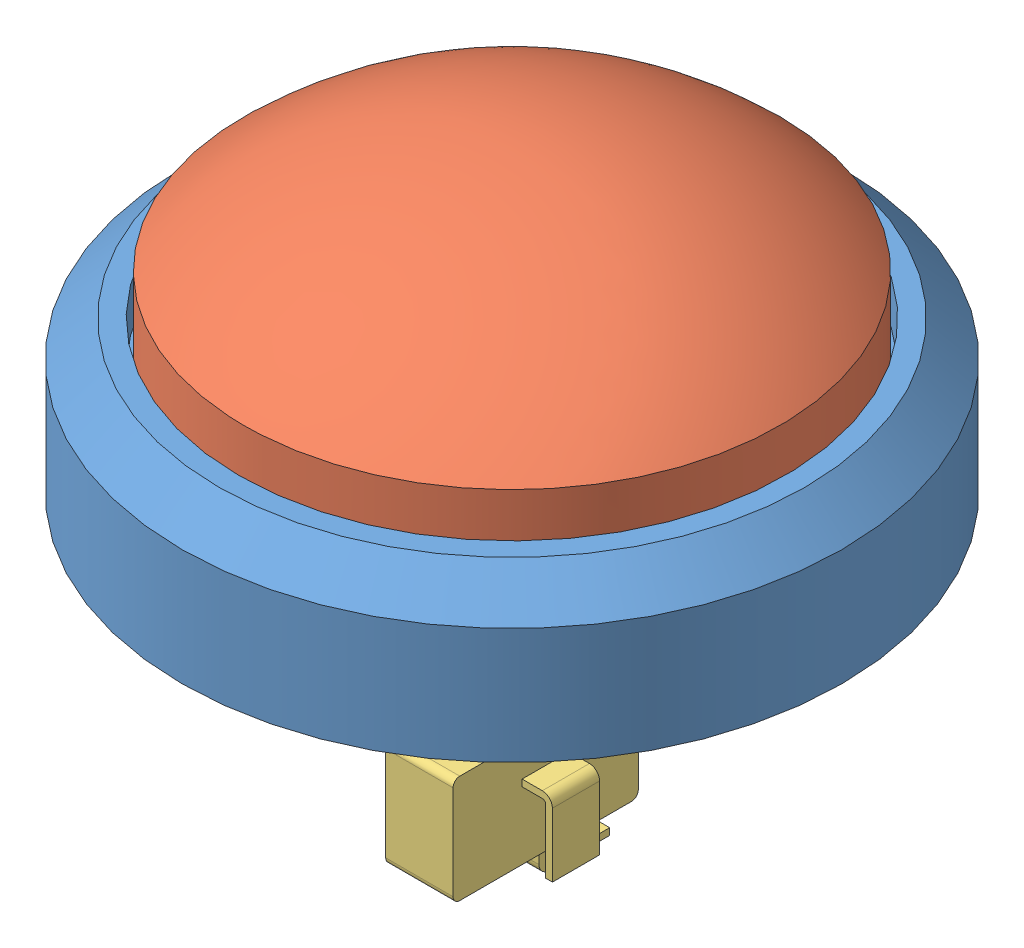
SolidWorks assembly Button Assembly, configuration Default. Lengths in mm.
Overall size (98 92.55 98).
3 component instances, 3 part files, 5 mates.
Components (placement in the parent):
- Button Shield-2: Button Shield [Default] at (4.0062 3.8785 -7.884) size (98 47.5 98)
- Button Dome-2: Button Dome [Default] at (4.0062 19.9285 -7.884) size (79.5 28.5 79.5)
- Microswitch-2: Microswitch [Default] at (4.0062 -39.6215 -21.634) x (0 0 1) z (-1 0 0) size (38 41 20)
Mates (geometry in assembly coordinates):
- Concentric1: concentric anti-aligned: cylinder of Button Shield-2 through (4.0062 19.8785 -7.884) axis (0 1 0) radius 40.5; cylinder of Button Dome-2 through (4.0062 32.4285 -7.884) axis (0 -1 0) radius 39.75
- Distance1: distance = 0.05 mm anti-aligned: plane of Button Shield-2 through (4.0062 19.8785 -7.884) normal (0 1 0); plane of Button Dome-2 through (4.0062 19.9285 -7.884) normal (0 -1 0)
- Coincident2: coincident anti-aligned: plane of Button Shield-2 through (4.0062 -21.1215 -7.884) normal (0 -1 0); plane of Microswitch-2 through (4.0062 -21.1215 -7.884) normal (0 1 0)
- Concentric2: concentric anti-aligned: cylinder of Button Shield-2 through (4.0062 -21.1215 -7.884) axis (0 1 0) radius 9; cylinder of Microswitch-2 through (4.0062 -3.1215 -7.884) axis (0 -1 0) radius 6
- Parallel1: parallel anti-aligned: plane of Microswitch-2 through (-0.9938 -24.6215 4.866) normal (-1 0 0); plane of assembly through (0 0 0) normal (1 0 0)
